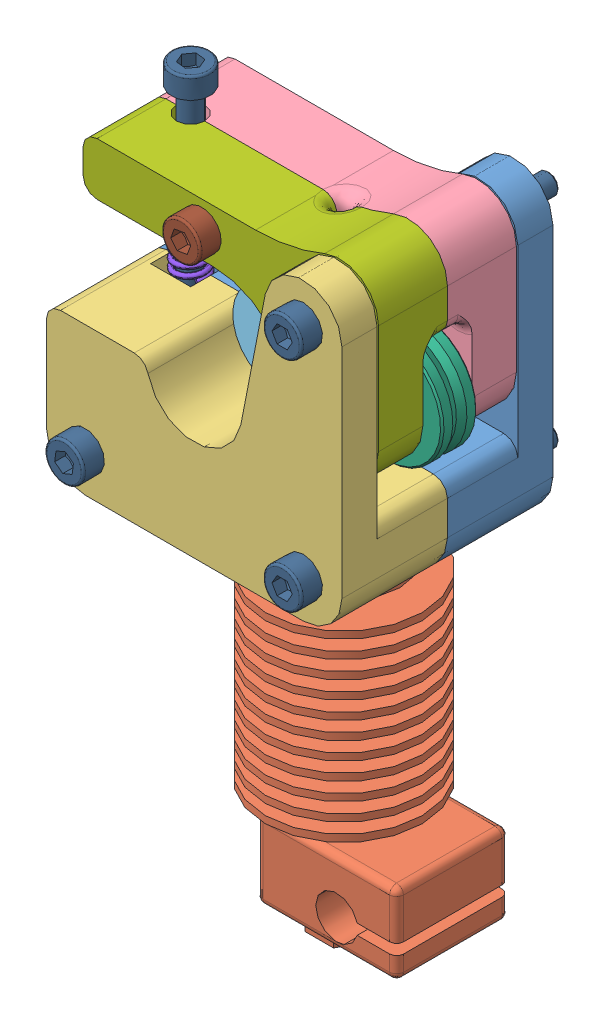
SolidWorks assembly EXTRUDER, configuration Default. Lengths in mm.
Overall size (45.88 97.6 38).
14 component instances, 11 part files, 26 mates.
Components (placement in the parent):
- EXTRUDER BODY-1: EXTRUDER BODY [Default] at origin size (42 42 15.16)
- E3Dv6-1: E3Dv6 [Default] at (6.2725 -52.5 15) size (26.65 62.8 22.3)
- EXTRUDER BODY_MIR-1: EXTRUDER BODY_MIR [Default] at (0 0 30) size (42 42 15.16)
- EXTRUDER ARM-1: EXTRUDER ARM [Default] at (0 0 15) size (42 27.23 9.86)
- HOBBED PULLEY-1: HOBBED PULLEY [Default] at (0 0 18.175) x (0.983892 -0.178763 0) z (0 0 -1) size (12.7 12.7 10.79)
- 625vv-1: 625vv [Default] at (14.7725 0 15) x (0 0 -1) z (0.949595 -0.313481 0) size (5 16 16)
- EXTRUDER ARM_MIR-1: EXTRUDER ARM_MIR [Default] at (0 0 15) size (42 27.23 9.86)
- EXTRUDER SPRING-1: EXTRUDER SPRING [Default] at (-15.5 12.05 15) x (-0.871551 0 -0.490306) z (-0.490306 0 0.871551) size (5.3 13.34 5.3)
- M3 SQUARE NUT-1: M3 SQUARE NUT [Default] at (-15.5 -5.689 15) x (0 1 0) z (-0.707107 0 -0.707107) size (1.8 7.78 7.78)
- M3X35-1: M3X35 [Default] at (-15.5 -15.5 30) x (0 0 -1) z (-0.126122 -0.992015 0) size (38 5.5 5.5)
- M3X35-2: M3X35 [Default] at (15.5 -15.5 30) x (0 0 -1) z (1 0 0) size (38 5.5 5.5)
- M3X35-3: M3X35 [Default] at (15.5 15.5 30) x (0 0 -1) z (1 0 0) size (38 5.5 5.5)
- M3X35-4: M3X35 [Default] at (-15.5 22 15) x (0 -1 0) z (-0.39793 0 -0.917416) size (38 5.5 5.5)
- M3X20-1: M3X20 [Default] at (-4.1138 14.8 24.8) x (0 0 -1) z (0.986058 0.166401 0) size (23 5.5 5.5)
Mates (geometry in assembly coordinates):
- Concentric1: concentric aligned: cylinder of EXTRUDER BODY-1 through (6.2725 -21 15) axis (0 1 0) radius 6.1; cylinder of E3Dv6-1 through (6.2725 -16.5 15) axis (0 1 0) radius 6
- Coincident1: coincident anti-aligned: plane of EXTRUDER BODY-1 through (6.2725 -19.5 15) normal (0 -1 0); plane of E3Dv6-1 through (-0.7275 -19.5 15) normal (0 1 0)
- Concentric2: concentric anti-aligned: cylinder of EXTRUDER BODY-1 through (0 0 0) axis (0 0 1) radius 6.75; cylinder of HOBBED PULLEY-1 through (0 0 10.555) axis (0 0 -1) radius 6.35
- Concentric3: concentric anti-aligned: cylinder of EXTRUDER BODY-1 through (15.5 15.5 5) axis (0 0 1) radius 2.9; cylinder of EXTRUDER ARM-1 through (15.5 15.5 15) axis (0 0 -1) radius 3
- Concentric4: concentric aligned: cylinder of EXTRUDER ARM-1 through (15.5 15.5 15) axis (0 0 -1) radius 3; cylinder of EXTRUDER ARM_MIR-1 through (15.5 15.5 15) axis (0 0 -1) radius 3
- Concentric5: concentric aligned: cylinder of EXTRUDER ARM-1 through (14.7725 0 15) axis (0 0 -1) radius 2.4; cylinder of 625vv-1 through (14.7725 0 15) axis (0 0 -1) radius 2.5
- Concentric7: concentric aligned: cylinder of EXTRUDER ARM-1 through (-4.1138 14.8 5.2) axis (0 0 1) radius 1.5; cylinder of EXTRUDER ARM_MIR-1 through (-4.1138 14.8 24.8) axis (0 0 1) radius 1.5
- Concentric8: concentric anti-aligned: cylinder of EXTRUDER ARM_MIR-1 through (-4.1138 14.8 24.8) axis (0 0 1) radius 1.5; cylinder of M3X20-1 through (-4.1138 14.8 14.3433) axis (0 0 -1) radius 1.5
- Coincident2: coincident anti-aligned: plane of EXTRUDER ARM_MIR-1 through (15.5 15.5 24.8) normal (0 0 1); plane of M3X20-1 through (-4.4674 16.8954 24.8) normal (0 0 -1)
- Coincident3: coincident anti-aligned: plane of EXTRUDER ARM-1 through (14.7725 0 12.5) normal (0 0 1); plane of 625vv-1 through (16.4183 4.9854 12.5) normal (0 0 -1)
- Coincident5: coincident anti-aligned: plane of EXTRUDER ARM-1 through (15.5 15.5 15) normal (0 0 1); plane of EXTRUDER ARM_MIR-1 through (15.5 15.5 15) normal (0 0 -1)
- Concentric9: concentric aligned: cylinder of EXTRUDER BODY-1 through (15.5 15.5 15) axis (0 0 -1) radius 1.6; cylinder of EXTRUDER BODY_MIR-1 through (15.5 15.5 15) axis (0 0 -1) radius 1.6
- Concentric10: concentric aligned: cylinder of EXTRUDER BODY-1 through (-15.5 -15.5 0) axis (0 0 1) radius 1.55; cylinder of EXTRUDER BODY_MIR-1 through (-15.5 -15.5 30) axis (0 0 1) radius 1.55
- Concentric19: concentric aligned: cylinder of M3 SQUARE NUT-1 through (-15.5 5.4573 15) axis (0 -1 0) radius 1.2295; cylinder of M3X35-4 through (-15.5 -4 15) axis (0 -1 0) radius 1.5
- Concentric20: concentric aligned: cylinder of EXTRUDER BODY-1 through (-15.5 -10 15) axis (0 -1 0) radius 1.6; cylinder of M3X35-4 through (-15.5 -4 15) axis (0 -1 0) radius 1.5
- Coincident14: coincident anti-aligned: plane of EXTRUDER BODY-1 through (-15.5 -13 15) normal (0 1 0); plane of M3X35-4 through (-16.1881 -13 15.2984) normal (0 -1 0)
- Parallel3: parallel anti-aligned: plane of EXTRUDER BODY-1 through (-18.35 0 12.15) normal (0 0 1); plane of M3 SQUARE NUT-1 through (-18.25 -5.689 12.25) normal (0 0 -1)
- Coincident16: coincident anti-aligned: plane of EXTRUDER BODY-1 through (0 0 15) normal (0 0 1); plane of EXTRUDER BODY_MIR-1 through (0 0 15) normal (0 0 -1)
- Concentric21: concentric anti-aligned: cylinder of EXTRUDER BODY-1 through (-15.5 -15.5 0) axis (0 0 1) radius 1.55; cylinder of M3X35-1 through (-15.5 -15.5 4) axis (0 0 -1) radius 1.5
- Coincident17: coincident anti-aligned: plane of EXTRUDER BODY_MIR-1 through (0 0 30) normal (0 0 1); plane of M3X35-1 through (-13.392 -15.768 30) normal (0 0 -1)
- Concentric22: concentric anti-aligned: cylinder of EXTRUDER BODY_MIR-1 through (15.5 -15.5 30) axis (0 0 1) radius 1.55; cylinder of M3X35-2 through (15.5 -15.5 4) axis (0 0 -1) radius 1.5
- Coincident18: coincident anti-aligned: plane of EXTRUDER BODY_MIR-1 through (0 0 30) normal (0 0 1); plane of M3X35-2 through (15.5 -13.375 30) normal (0 0 -1)
- Concentric23: concentric aligned: cylinder of EXTRUDER BODY-1 through (15.5 15.5 15) axis (0 0 -1) radius 1.6; cylinder of M3X35-3 through (15.5 15.5 4) axis (0 0 -1) radius 1.5
- Concentric24: concentric anti-aligned: cylinder of EXTRUDER ARM_MIR-1 through (-15.5 18.55 15) axis (0 1 0) radius 2; cylinder of M3X35-4 through (-15.5 -4 15) axis (0 -1 0) radius 1.5
- Coincident19: coincident anti-aligned: plane of EXTRUDER BODY_MIR-1 through (0 0 30) normal (0 0 1); plane of M3X35-3 through (15.5 17.625 30) normal (0 0 -1)
- Distance1: distance = 11.825 mm aligned: plane of HOBBED PULLEY-1 through (4.3537 -0.791 18.175) normal (0 0 1); plane of EXTRUDER BODY_MIR-1 through (0 0 30) normal (0 0 1)
